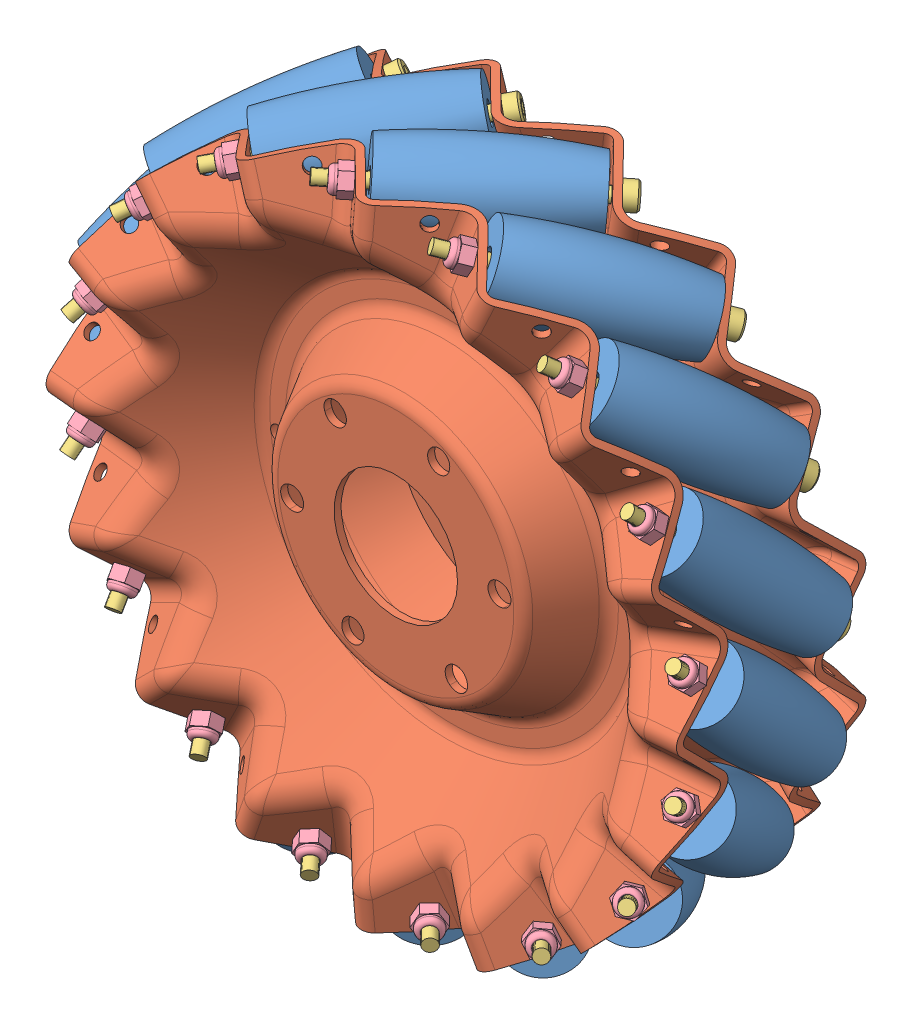
SolidWorks assembly 6-mecanum-asm_2, configuration По умолчанию. Lengths in mm.
Overall size (168 168 48.1).
50 component instances, 4 part files, 0 mates.
Components (placement in the parent):
- 1_2-1: 1_2 [По умолчанию] at (8.6353 -68.1585 13.5596) x (0.707903 0.00698 -0.706275) z (0.704722 -0.073989 0.705615) size (17.82 17.82 38.1)
- 1_2-2: 1_2 [По умолчанию] at (-18.1052 -66.2749 13.5596) x (0.656689 -0.264454 -0.706275) z (0.622763 -0.338043 0.705615) size (17.82 17.82 38.1)
- 1_2-3: 1_2 [По умолчанию] at (34.0611 -59.6657 13.5596) x (0.651346 0.277352 -0.706275) z (0.679392 0.201328 0.705615) size (17.82 17.82 38.1)
- 1_2-4: 1_2 [По умолчанию] at (54.3015 -42.0893 13.5596) x (0.495627 0.505499 -0.706275) z (0.550632 0.445995 0.705615) size (17.82 17.82 38.1)
- 1_2-5: 1_2 [По умолчанию] at (66.2749 -18.1052 13.5596) x (0.264454 0.656689 -0.706275) z (0.338043 0.622763 0.705615) size (17.82 17.82 38.1)
- 1_2-6: 1_2 [По умолчанию] at (68.1585 8.6353 13.5596) x (-0.00698 0.707903 -0.706275) z (0.073989 0.704722 0.705615) size (17.82 17.82 38.1)
- 1_2-7: 1_2 [По умолчанию] at (59.6657 34.0611 13.5596) x (-0.277352 0.651346 -0.706275) z (-0.201328 0.679392 0.705615) size (17.82 17.82 38.1)
- 1_2-8: 1_2 [По умолчанию] at (42.0893 54.3015 13.5596) x (-0.505499 0.495627 -0.706275) z (-0.445995 0.550632 0.705615) size (17.82 17.82 38.1)
- 1_2-9: 1_2 [По умолчанию] at (18.1052 66.2749 13.5596) x (-0.656689 0.264454 -0.706275) z (-0.622763 0.338043 0.705615) size (17.82 17.82 38.1)
- 1_2-10: 1_2 [По умолчанию] at (-8.6353 68.1585 13.5596) x (-0.707903 -0.00698 -0.706275) z (-0.704722 0.073989 0.705615) size (17.82 17.82 38.1)
- 1_2-11: 1_2 [По умолчанию] at (-34.0611 59.6657 13.5596) x (-0.651346 -0.277352 -0.706275) z (-0.679392 -0.201328 0.705615) size (17.82 17.82 38.1)
- 1_2-12: 1_2 [По умолчанию] at (-54.3015 42.0893 13.5596) x (-0.495627 -0.505499 -0.706275) z (-0.550632 -0.445995 0.705615) size (17.82 17.82 38.1)
- 1_2-13: 1_2 [По умолчанию] at (-66.2749 18.1052 13.5596) x (-0.264454 -0.656689 -0.706275) z (-0.338043 -0.622763 0.705615) size (17.82 17.82 38.1)
- 1_2-14: 1_2 [По умолчанию] at (-68.1585 -8.6353 13.5596) x (0.00698 -0.707903 -0.706275) z (-0.073989 -0.704722 0.705615) size (17.82 17.82 38.1)
- 1_2-15: 1_2 [По умолчанию] at (-59.6657 -34.0611 13.5596) x (0.277352 -0.651346 -0.706275) z (0.201328 -0.679392 0.705615) size (17.82 17.82 38.1)
- 1_2-16: 1_2 [По умолчанию] at (-42.0893 -54.3015 13.5596) x (0.505499 -0.495627 -0.706275) z (0.445995 -0.550632 0.705615) size (17.82 17.82 38.1)
- 2_1-1: 2_1 [По умолчанию] at origin size (142.88 142.88 24.13)
- 2_1-2: 2_1 [По умолчанию] at (0 0 -3.2004) x (0.980785 0.19509 0) z (0 0 -1) size (142.88 142.88 24.13)
- M3SHCS_1-1: M3SHCS_1 [По умолчанию] at (-51.7387 44.8846 -16.7826) x (0.611825 -0.715121 -0.338043) z (0.338043 0.622763 -0.705615) size (5.5 5.5 53)
- M3SHCS_1-2: M3SHCS_1 [По умолчанию] at (-30.6237 61.2675 -16.7826) x (-0.02993 -0.834211 -0.550632) z (0.550632 0.445995 -0.705615) size (5.5 5.5 53)
- M3SHCS_1-3: M3SHCS_1 [По умолчанию] at (-4.8465 68.323 -16.7826) x (-0.567928 -0.464632 -0.679392) z (0.679392 0.201328 -0.705615) size (5.5 5.5 53)
- M3SHCS_1-4: M3SHCS_1 [По умолчанию] at (-64.9769 21.6685 -16.7826) x (0.981404 -0.177122 -0.073989) z (0.073989 0.704722 -0.705615) size (5.5 5.5 53)
- M3SHCS_1-5: M3SHCS_1 [По умолчанию] at (-68.323 -4.8465 -16.7826) x (0.862313 0.464632 0.201328) z (-0.201328 0.679392 -0.705615) size (5.5 5.5 53)
- M3SHCS_1-6: M3SHCS_1 [По умолчанию] at (-61.2675 -30.6237 -16.7826) x (0.324314 0.834211 0.445995) z (-0.445995 0.550632 -0.705615) size (5.5 5.5 53)
- M3SHCS_1-7: M3SHCS_1 [По умолчанию] at (-44.8846 -51.7387 -16.7826) x (-0.31744 0.715121 0.622763) z (-0.622763 0.338043 -0.705615) size (5.5 5.5 53)
- M3SHCS_1-8: M3SHCS_1 [По умолчанию] at (-21.6685 -64.9769 -16.7826) x (-0.687019 0.177122 0.704722) z (-0.704722 0.073989 -0.705615) size (5.5 5.5 53)
- M3SHCS_1-9: M3SHCS_1 [По умолчанию] at (4.8465 -68.323 -16.7826) x (-0.567928 -0.464632 0.679392) z (-0.679392 -0.201328 -0.705615) size (5.5 5.5 53)
- M3SHCS_1-10: M3SHCS_1 [По умолчанию] at (30.6237 -61.2675 -16.7826) x (-0.02993 -0.834211 0.550632) z (-0.550632 -0.445995 -0.705615) size (5.5 5.5 53)
- M3SHCS_1-11: M3SHCS_1 [По умолчанию] at (51.7387 -44.8846 -16.7826) x (0.611825 -0.715121 0.338043) z (-0.338043 -0.622763 -0.705615) size (5.5 5.5 53)
- M3SHCS_1-12: M3SHCS_1 [По умолчанию] at (64.9769 -21.6685 -16.7826) x (0.981404 -0.177122 0.073989) z (-0.073989 -0.704722 -0.705615) size (5.5 5.5 53)
- M3SHCS_1-13: M3SHCS_1 [По умолчанию] at (68.323 4.8465 -16.7826) x (0.862313 0.464632 -0.201328) z (0.201328 -0.679392 -0.705615) size (5.5 5.5 53)
- M3SHCS_1-14: M3SHCS_1 [По умолчанию] at (44.8846 51.7387 -16.7826) x (-0.31744 0.715121 -0.622763) z (0.622763 -0.338043 -0.705615) size (5.5 5.5 53)
- M3SHCS_1-15: M3SHCS_1 [По умолчанию] at (21.6685 64.9769 -16.7826) x (-0.687019 0.177122 -0.704722) z (0.704722 -0.073989 -0.705615) size (5.5 5.5 53)
- M3SHCS_1-16: M3SHCS_1 [По умолчанию] at (61.2675 30.6237 -16.7826) x (0.324314 0.834211 -0.445995) z (0.445995 -0.550632 -0.705615) size (5.5 5.5 53)
- M3Nyloc_1-1: M3Nyloc_1 [По умолчанию] at (66.0647 -18.0826 13.5822) x (0.936151 -0.121324 -0.330002) z (0.330002 0.627061 0.705615) size (6.35 5.5 4.25)
- M3Nyloc_1-2: M3Nyloc_1 [По умолчанию] at (54.1159 -41.988 13.5822) x (0.825952 -0.144722 -0.544848) z (0.544848 0.453042 0.705615) size (6.35 5.5 4.25)
- M3Nyloc_1-3: M3Nyloc_1 [По умолчанию] at (33.9285 -59.5011 13.5822) x (0.731484 -0.083344 -0.676746) z (0.676746 0.210052 0.705615) size (6.35 5.5 4.25)
- M3Nyloc_1-4: M3Nyloc_1 [По умолчанию] at (8.5757 -67.9557 13.5822) x (0.708086 0.026856 -0.705615) z (0.705615 -0.064917 0.705615) size (6.35 5.5 4.25)
- M3Nyloc_1-5: M3Nyloc_1 [По умолчанию] at (-67.9557 -8.5757 13.5822) x (0.997529 -0.026856 0.064917) z (-0.064917 -0.705615 0.705615) size (6.35 5.5 4.25)
- M3Nyloc_1-6: M3Nyloc_1 [По умолчанию] at (-18.0826 -66.0647 13.5822) x (0.769464 0.121324 -0.627061) z (0.627061 -0.330002 0.705615) size (6.35 5.5 4.25)
- M3Nyloc_1-7: M3Nyloc_1 [По умолчанию] at (-41.988 -54.1159 13.5822) x (0.879664 0.144722 -0.453042) z (0.453042 -0.544848 0.705615) size (6.35 5.5 4.25)
- M3Nyloc_1-8: M3Nyloc_1 [По умолчанию] at (67.9557 8.5757 13.5822) x (0.997529 -0.026856 -0.064917) z (0.064917 0.705615 0.705615) size (6.35 5.5 4.25)
- M3Nyloc_1-9: M3Nyloc_1 [По умолчанию] at (-59.5011 -33.9285 13.5822) x (0.974131 0.083344 -0.210052) z (0.210052 -0.676746 0.705615) size (6.35 5.5 4.25)
- M3Nyloc_1-10: M3Nyloc_1 [По умолчанию] at (59.5011 33.9285 13.5822) x (0.974131 0.083344 0.210052) z (-0.210052 0.676746 0.705615) size (6.35 5.5 4.25)
- M3Nyloc_1-11: M3Nyloc_1 [По умолчанию] at (-66.0647 18.0826 13.5822) x (0.936151 -0.121324 0.330002) z (-0.330002 -0.627061 0.705615) size (6.35 5.5 4.25)
- M3Nyloc_1-12: M3Nyloc_1 [По умолчанию] at (-54.1159 41.988 13.5822) x (0.825952 -0.144722 0.544848) z (-0.544848 -0.453042 0.705615) size (6.35 5.5 4.25)
- M3Nyloc_1-13: M3Nyloc_1 [По умолчанию] at (-33.9285 59.5011 13.5822) x (0.731484 -0.083344 0.676746) z (-0.676746 -0.210052 0.705615) size (6.35 5.5 4.25)
- M3Nyloc_1-14: M3Nyloc_1 [По умолчанию] at (18.0826 66.0647 13.5822) x (0.769464 0.121324 0.627061) z (-0.627061 0.330002 0.705615) size (6.35 5.5 4.25)
- M3Nyloc_1-15: M3Nyloc_1 [По умолчанию] at (-8.5757 67.9557 13.5822) x (0.708086 0.026856 0.705615) z (-0.705615 0.064917 0.705615) size (6.35 5.5 4.25)
- M3Nyloc_1-16: M3Nyloc_1 [По умолчанию] at (41.988 54.1159 13.5822) x (0.879664 0.144722 0.453042) z (-0.453042 0.544848 0.705615) size (6.35 5.5 4.25)
